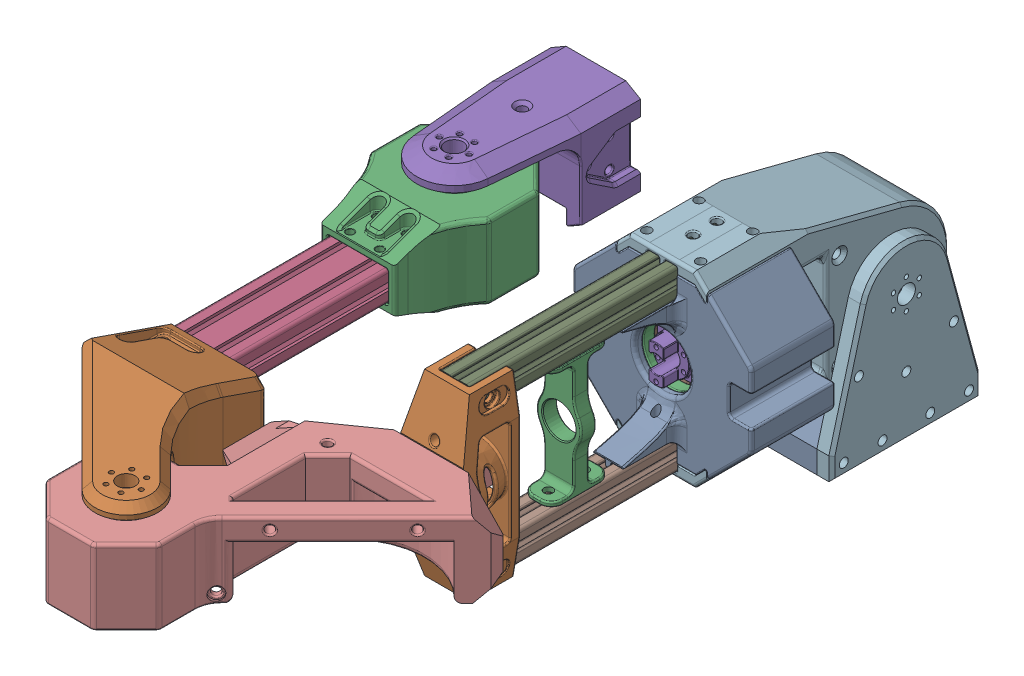
SolidWorks assembly ShinTheseusofc(2), configuration Valor predeterminado. Lengths in mm.
Overall size (259.74 148 493.1).
17 component instances, 17 part files, 0 mates.
Components (placement in the parent):
- cyc11a-1: cyc11a [Valor predeterminado] at origin size (48.4 48.78 4)
- cyc11a (1)-1: cyc11a (1) [Valor predeterminado] at (0.1298 0 4) x (-1 0 0) z (0 0 1) size (48.4 48.78 4)
- Facecap-1: Facecap [Valor predeterminado] at (0 0 38) size (70 70 16.04)
- Backcap-1: Backcap [Valor predeterminado] at (0 0 -1) size (70 70 16)
- Carrier121-1: Carrier121 [Valor predeterminado] at origin size (40 40 27.81)
- subcarrierA-1: subcarrierA [Valor predeterminado] at origin size (40 40 10)
- subcarrierB-1: subcarrierB [Valor predeterminado] at origin size (13.66 12 16)
- axle121-1: axle121 [Valor predeterminado] at origin size (15.32 12.03 40)
- cyc11a (2)-1: cyc11a (2) [Valor predeterminado] at origin size (48.4 48.78 4)
- cyc11a (1) (1)-1: cyc11a (1) (1) [Valor predeterminado] at origin size (48.4 48.78 4)
- shell121-1: shell121 [Valor predeterminado] at origin size (70 70 33)
- XouderJoint-1: XouderJoint [Valor predeterminado] at origin size (60.03 126.01 163)
- XouderTwist-1: XouderTwist [Valor predeterminado] at origin size (120.06 110.1 92.06)
- EubouTwist-1: EubouTwist [Valor predeterminado] at origin size (50.34 120 40.01)
- Holder-1: Holder [Valor predeterminado] at origin size (30 80 40)
- 5537T912_T-Slotted Framing-1: 5537T912_T-Slotted Framing [Valor predeterminado] at (0 -250 0) size (40 20 186.7)
- eBom-FreeParts-1: eBom-FreeParts [Valor predeterminado] at origin size (258.16 145 493.1)
